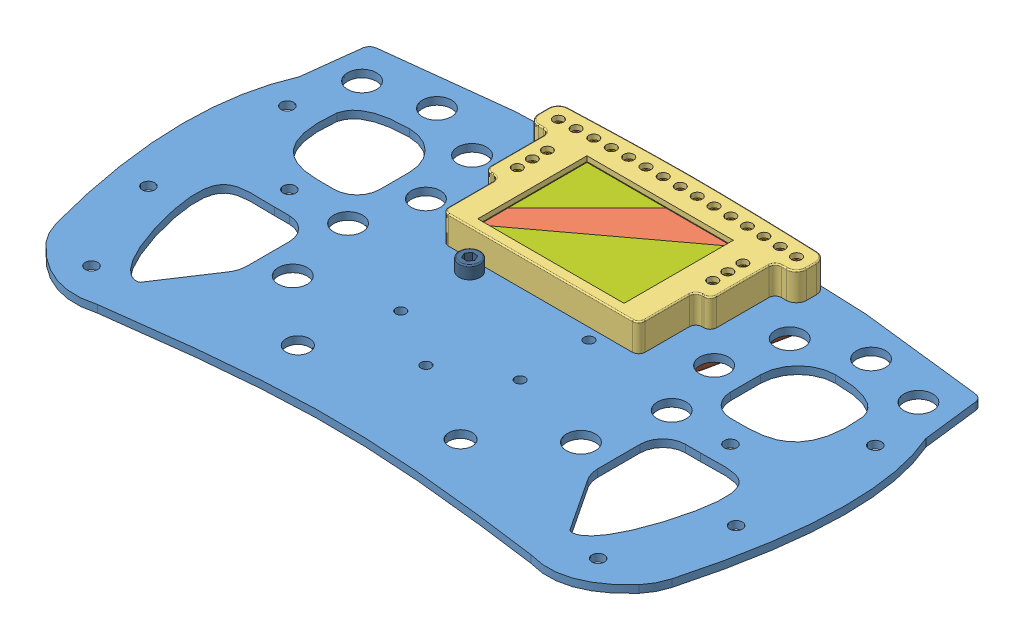
SolidWorks assembly Assem, configuration Default. Lengths in mm.
Overall size (280.62 24.72 158.02).
15 component instances, 15 part files, 52 mates.
Components (placement in the parent):
- Bara G27 bas-1: Bara G27 bas [Default] at (-7.1603 -4.9738 15.1461) size (210 32 120) (hidden)
- 1.0 Axel A SLDPRT-1: 1.0 Axel A SLDPRT [Default] at (-7.1603 35.0262 15.1461) size (280.62 3 157.95)
- Waveshare 19173-1: Waveshare 19173 [Default] at (-42.1103 40.1262 -5.1539) size (65.7 11 47.8)
- Electronics cover-1: Electronics cover [Default] at (-393.8051 47.1262 18.4993) size (107 11.1 62.5)
- Raspberry Pi Pico-R3-1: Raspberry Pi Pico-R3 [Default] at (-9.1014 29.4862 -35.0083) x (0 0 -1) z (-1 0 0) size (21 3.69 52.43)
- Raspberry Pi Zero 2 W-1: Raspberry Pi Zero 2 W [Default] at (-8.8103 30.7862 -37.4139) size (65.8 5.05 30.58)
- 61004021821 (rev1)-1: 61004021821 (rev1) [Default] at (-8.9903 37.7462 -48.7339) x (1 0 0) z (0 -1 0) size (51.3 6.7 7.45) (hidden)
- 61304021121 (rev1)-1: 61304021121 (rev1) [Default] at (-8.8103 32.8562 -47.6439) size (50.8 11.54 5.08)
- Board outline-1: Board outline [Default] at (40.3397 41.5762 -57.7057) size (99.8 1.6 36.3) (hidden)
- Spacer Display-1: Spacer Display [Default] at (21.9121 37.3704 -37.0654) size (85.6 11 48.6)
- pin header spacer-1: pin header spacer [Default] at (29.9194 32.8562 -40.8469) size (50.8 11.54 5.08)
- PCB-2: PCB [Default] at (-59.6603 45.6176 -28.3039) x (1 0 0) z (0 1 0) size (99.8 34.3 9.39)
- Screw-1: Screw [Default] at (-30.976 38.0262 1.3961) x (0.994617 0 0.103616) z (-0.103616 0 0.994617) size (8.5 5 8.5)
- Back cover-1: Back cover [Default] at (-53.2603 26.0262 -57.8037) size (105.24 9.61 46.25)
- Spacer_3d-2: Spacer_3d [Default] at (-7.1603 35.0262 15.1461) x (0.5 0 0.866025) z (0.866025 0 -0.5) size (75 10 75)
Mates (geometry in assembly coordinates):
- Concentric1: concentric anti-aligned: cylinder of Bara G27 bas-1 through (-30.976 23.0262 1.3961) axis (0 1 0) radius 2; cylinder of 1.0 Axel A SLDPRT-1 through (-30.976 38.0262 1.3961) axis (0 -1 0) radius 2
- Concentric2: concentric anti-aligned: cylinder of Bara G27 bas-1 through (16.6554 23.0262 28.8961) axis (0 1 0) radius 2; cylinder of 1.0 Axel A SLDPRT-1 through (16.6554 38.0262 28.8961) axis (0 -1 0) radius 2
- Coincident2: coincident anti-aligned: plane of 1.0 Axel A SLDPRT-1 through (-7.1603 38.0262 15.1461) normal (0 1 0); plane of HyperPixel 4-1 through (-40.8157 28.0262 -6.2082) normal (0 -1 0)
- Coincident3: coincident anti-aligned: plane of 1.0 Axel A SLDPRT-1 through (-7.1603 38.0262 15.1461) normal (0 1 0); plane of Spacer Display-1 through (21.9121 38.0262 -37.0654) normal (0 -1 0)
- Coincident4: coincident anti-aligned: plane of Waveshare 19173-1 through (-42.1103 47.1262 -5.1539) normal (0 1 0); plane of Electronics cover-1 through (-393.8051 47.1262 18.4993) normal (0 -1 0)
- Distance3: distance = 0.2 mm aligned: plane of Electronics cover-1 through (-393.8051 49.1262 -50.8039) normal (0 0 1); plane of Waveshare 19173-1 through (-36.1603 47.0262 -50.6039) normal (0 0 1)
- Distance5: distance = 0.2 mm aligned: plane of Waveshare 19173-1 through (-36.1603 47.0262 -50.6039) normal (1 0 0); plane of Electronics cover-1 through (-36.3603 49.1262 18.4993) normal (1 0 0)
- Parallel1: parallel aligned: plane of Bara G27 bas-1 through (-7.1603 25.0262 -34.3539) normal (0 0 -1); plane of Raspberry Pi Zero 2 W-1 through (-41.3103 31.5862 -52.4139) normal (0 0 -1)
- Coincident12: coincident anti-aligned: plane of Bara G27 bas-1 through (-7.1603 25.0262 15.1461) normal (0 1 0); plane of Spacer_3d-1 through (-7.1603 25.0262 15.1461) normal (0 -1 0)
- Concentric3: concentric anti-aligned: cylinder of Bara G27 bas-1 through (-30.976 23.0262 28.8961) axis (0 1 0) radius 2; cylinder of Spacer_3d-1 through (-30.976 35.0262 28.8961) axis (0 -1 0) radius 2.25
- Concentric4: concentric anti-aligned: cylinder of Bara G27 bas-1 through (-7.1603 23.0262 -12.3539) axis (0 1 0) radius 2; cylinder of Spacer_3d-1 through (-7.1603 35.0262 -12.3539) axis (0 -1 0) radius 2.25
- Concentric5: concentric aligned: cylinder of 1.0 Axel A SLDPRT-1 through (-7.1603 38.0262 -12.3539) axis (0 -1 0) radius 2; cylinder of Spacer_3d-1 through (-7.1603 35.0262 -12.3539) axis (0 -1 0) radius 2.25
- Coincident13: coincident anti-aligned: plane of 1.0 Axel A SLDPRT-1 through (-7.1603 35.0262 15.1461) normal (0 -1 0); plane of Spacer_3d-1 through (-7.1603 35.0262 15.1461) normal (0 1 0)
- Concentric7: concentric anti-aligned: cylinder of 1.0 Axel A SLDPRT-1 through (38.9397 35.0262 -57.8037) axis (0 1 0) radius 1.75; cylinder of Back cover-1 through (38.9397 27.0262 -57.8037) axis (0 -1 0) radius 1.75
- Concentric8: concentric anti-aligned: cylinder of 1.0 Axel A SLDPRT-1 through (-53.2603 35.0262 -57.8037) axis (0 1 0) radius 1.75; cylinder of Back cover-1 through (-53.2603 27.0262 -57.8037) axis (0 -1 0) radius 1.75
- Coincident17: coincident anti-aligned: plane of 1.0 Axel A SLDPRT-1 through (-7.1603 35.0262 15.1461) normal (0 -1 0); plane of Back cover-1 through (-53.2603 35.0262 -57.8037) normal (0 1 0)
- Coincident21: coincident anti-aligned: plane of 61004021821 (rev1)-1 through (15.6397 86.183 -50.5039) normal (0 0 1); plane of 61304021121 (rev1)-1 through (15.3197 34.3562 -50.5039) normal (0 0 -1)
- Coincident22: coincident anti-aligned: plane of 61004021821 (rev1)-1 through (15.6397 86.183 -49.5039) normal (-1 0 0); plane of 61304021121 (rev1)-1 through (15.6397 40.1262 -50.5039) normal (1 0 0)
- Coincident23: coincident anti-aligned: plane of 61004021821 (rev1)-1 through (-34.6403 34.1262 -51.2739) normal (0 -1 0); plane of 61304021121 (rev1)-1 through (16.5897 34.1262 -46.3739) normal (0 1 0)
- Parallel3: parallel aligned: plane of Raspberry Pi Zero 2 W-1 through (-41.3103 31.5862 -52.4139) normal (0 0 -1); plane of 61304021121 (rev1)-1 through (16.5897 31.5862 -51.4539) normal (0 0 -1)
- Concentric9: concentric anti-aligned: cylinder of Electronics cover-1 through (-47.8787 49.1262 -58.006) axis (0 -1 0) radius 2; cylinder of 1.0 Axel A SLDPRT-1 through (-47.8787 35.0262 -58.006) axis (0 1 0) radius 1.75
- Concentric10: concentric anti-aligned: cylinder of Electronics cover-1 through (33.5581 49.1262 -58.006) axis (0 -1 0) radius 2; cylinder of 1.0 Axel A SLDPRT-1 through (33.5581 35.0262 -58.006) axis (0 1 0) radius 1.75
- Coincident29: coincident anti-aligned: plane of 61004021821 (rev1)-1 through (0.2197 41.5762 -46.5039) normal (0 1 0); plane of Board outline-1 through (40.3397 41.5762 -57.7057) normal (0 -1 0)
- Parallel5: parallel anti-aligned: plane of 1.0 Axel A SLDPRT-1 through (-7.1603 35.0262 -38.3539) normal (0 0 -1); plane of Board outline-1 through (40.3397 43.1762 -51.9539) normal (0 0 1)
- Concentric11: concentric aligned: circle of Electronics cover-1; circle of Board outline-1
- Coincident31: coincident aligned: plane of 61304021121 (rev1)-1 through (16.5897 31.5862 -46.3739) normal (0 0 1); plane of PCB-1 through (-33.5775 40.612 -55.2739) normal (0 0 1)
- Coincident32: coincident anti-aligned: plane of 61304021121 (rev1)-1 through (16.5897 34.1262 -46.3739) normal (0 1 0); plane of PCB-1 through (-7.9275 33.012 -57.8139) normal (0 -1 0)
- Coincident33: coincident aligned: plane of 61304021121 (rev1)-1 through (-34.2103 32.8562 -47.6439) normal (-1 0 0); plane of PCB-1 through (-33.5775 40.612 -60.3539) normal (-1 0 0)
- Coincident34: coincident anti-aligned: plane of 1.0 Axel A SLDPRT-1 through (-7.1603 35.0262 -60.3539) normal (0 0 1); plane of PCB-1 through (17.7225 40.612 -60.3539) normal (0 0 -1)
- Distance6: distance = 1 mm anti-aligned: plane of Waveshare 19173-1 through (-34.4103 36.1262 -46.4539) normal (0 0 1); plane of Spacer Display-1 through (21.9121 38.0262 -45.4539) normal (0 0 -1)
- Distance7: distance = 1 mm anti-aligned: plane of Spacer Display-1 through (-35.4103 38.0262 -37.0654) normal (1 0 0); plane of Waveshare 19173-1 through (-34.4103 36.1262 -46.4539) normal (-1 0 0)
- Coincident37: coincident anti-aligned: plane of Waveshare 19173-1 through (-42.1103 40.1262 -5.1539) normal (0 -1 0); plane of Spacer Display-1 through (21.9121 40.1262 -37.0654) normal (0 1 0)
- Coincident38: coincident aligned: plane of Waveshare 19173-1 through (-34.4103 36.1262 -51.4539) normal (0 0 -1); plane of 61304021121 (rev1)-1 through (16.5897 31.5862 -51.4539) normal (0 0 -1)
- Coincident39: coincident aligned: plane of Waveshare 19173-1 through (16.5897 36.1262 -46.4539) normal (1 0 0); plane of 61304021121 (rev1)-1 through (16.5897 32.8562 -47.6439) normal (1 0 0)
- Coincident40: coincident anti-aligned: plane of Waveshare 19173-1 through (-42.1103 36.1262 -5.1539) normal (0 -1 0); plane of pin header spacer-1 through (29.9194 36.1262 -40.8469) normal (0 1 0)
- Coincident41: coincident anti-aligned: plane of Raspberry Pi Zero 2 W-1 through (-8.8103 31.5862 -37.4139) normal (0 1 0); plane of 61304021121 (rev1)-1 through (16.5897 31.5862 -48.9139) normal (0 -1 0)
- Distance8: distance = 8.05 mm aligned: plane of 61304021121 (rev1)-1 through (-33.2603 28.5862 -50.5039) normal (-1 0 0); plane of Raspberry Pi Zero 2 W-1 through (-41.3103 31.5862 -52.4139) normal (-1 0 0)
- Distance9: distance = 1.91 mm aligned: plane of 61304021121 (rev1)-1 through (-32.9403 34.3562 -50.5039) normal (0 0 -1); plane of Raspberry Pi Zero 2 W-1 through (-41.3103 31.5862 -52.4139) normal (0 0 -1)
- Coincident44: coincident anti-aligned: plane of 61304021121 (rev1)-1 through (16.5897 34.1262 -46.3739) normal (0 1 0); plane of pin header spacer-1 through (29.9194 34.1262 -40.8469) normal (0 -1 0)
- Coincident45: coincident aligned: plane of 61304021121 (rev1)-1 through (16.5897 32.8562 -47.6439) normal (1 0 0); plane of pin header spacer-1 through (16.5897 36.1262 -40.8469) normal (1 0 0)
- Coincident46: coincident aligned: plane of 61304021121 (rev1)-1 through (16.5897 31.5862 -51.4539) normal (0 0 -1); plane of pin header spacer-1 through (29.9194 36.1262 -51.4539) normal (0 0 -1)
- Coincident47: coincident anti-aligned: plane of Raspberry Pi Pico-R3-1 through (-9.1014 29.9862 -35.0083) normal (0 1 0); plane of Raspberry Pi Zero 2 W-1 through (-8.8103 29.9862 -37.4139) normal (0 -1 0)
- Coincident48: coincident anti-aligned: plane of 1.0 Axel A SLDPRT-1 through (-7.1603 38.0262 15.1461) normal (0 1 0); plane of PCB-2 through (-53.2603 38.0262 -57.8039) normal (0 -1 0)
- Parallel10: parallel: line of Electronics cover-1 through (-36.3603 49.1262 -7.2039) axis (1 0 0); plane of PCB-2 through (-43.1103 44.0262 -28.3039) normal (0 0 1)
- Concentric12: concentric aligned: circle of 1.0 Axel A SLDPRT-1; cylinder of PCB-2 through (31.8397 40.0262 -32.8039) axis (0 1 0) radius 1.2295
- Concentric13: concentric aligned: cylinder of 1.0 Axel A SLDPRT-1 through (-30.976 38.0262 1.3961) axis (0 -1 0) radius 2; cylinder of Screw-1 through (-30.976 43.0262 1.3961) axis (0 -1 0) radius 4.25
- Concentric14: concentric anti-aligned: cylinder of 1.0 Axel A SLDPRT-1 through (-53.2603 35.0262 -57.8037) axis (0 1 0) radius 1.75; cylinder of Back cover-1 through (-53.2603 27.0262 -57.8037) axis (0 -1 0) radius 1.75
- Coincident49: coincident anti-aligned: plane of 1.0 Axel A SLDPRT-1 through (-7.1603 38.0262 15.1461) normal (0 1 0); plane of Screw-1 through (-30.976 38.0262 1.3961) normal (0 -1 0)
- Coincident53: coincident anti-aligned: plane of Bara G27 bas-1 through (-7.1603 25.0262 15.1461) normal (0 1 0); plane of Spacer_3d-2 through (-7.1603 25.0262 15.1461) normal (0 -1 0)
- Concentric17: concentric anti-aligned: cylinder of 1.0 Axel A SLDPRT-1 through (-7.1603 38.0262 -12.3539) axis (0 -1 0) radius 2; cylinder of Spacer_3d-2 through (-7.1603 25.0262 -12.3539) axis (0 1 0) radius 2.25
- Concentric19: concentric anti-aligned: cylinder of 1.0 Axel A SLDPRT-1 through (-30.976 38.0262 1.3961) axis (0 -1 0) radius 2; cylinder of Spacer_3d-2 through (-30.976 25.0262 1.3961) axis (0 1 0) radius 2.25
- Coincident54: coincident anti-aligned: plane of 1.0 Axel A SLDPRT-1 through (-7.1603 35.0262 15.1461) normal (0 -1 0); plane of Spacer_3d-2 through (-7.1603 35.0262 15.1461) normal (0 1 0)
